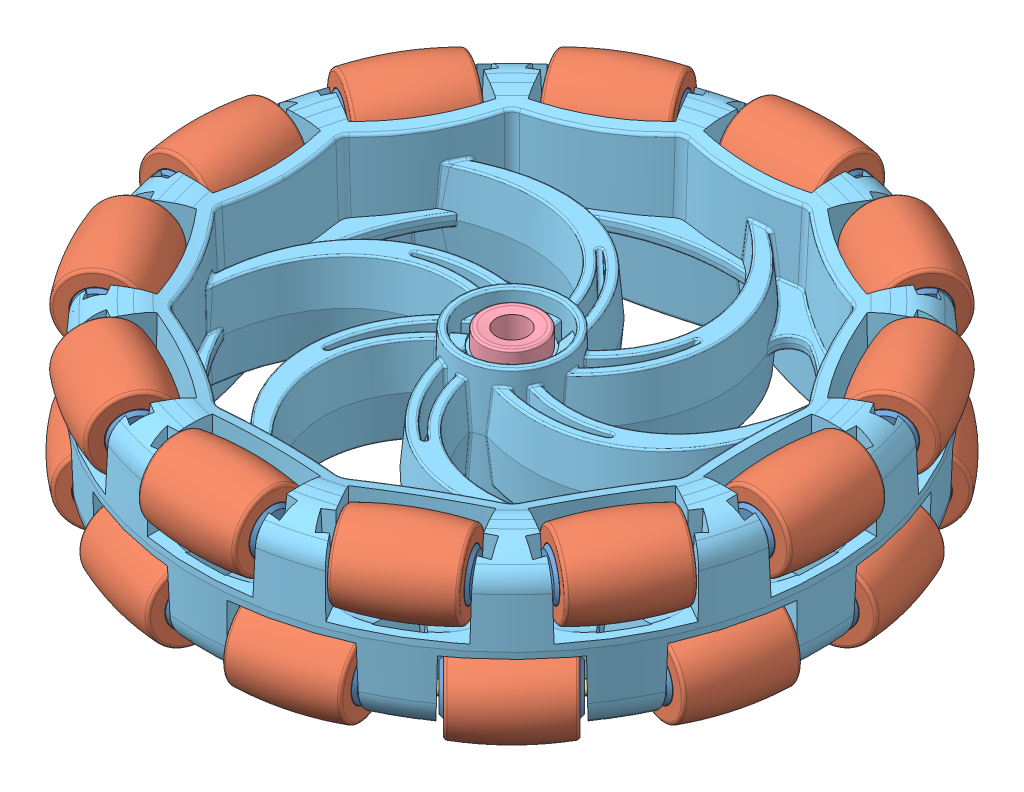
SolidWorks assembly LARGE-OMNI-WHEEL, configuration Default. Lengths in mm.
Overall size (108.3 29.85 108.3).
98 component instances, 5 part files, 0 mates.
Components (placement in the parent):
- OMNI-ROLLER-1: OMNI-ROLLER [Default] at (23.2326 8 -40.2802) x (0.866025 0 0.5) z (-0.5 0 0.866025) size (22 13.22 13.22)
  - ROLLER-INSERT-1: ROLLER-INSERT [Default] at origin size (16.6 8 8)
  - ROLLER-RUBBER-1: ROLLER-RUBBER [Default] at origin size (15.6 13.22 13.22)
  - ROLLER-SHAFT-1: ROLLER-SHAFT [Default] at origin size (22 2 2)
- OMNI-ROLLER-2: OMNI-ROLLER [Default] at (40.2671 8 23.2553) x (0.5 0 -0.866025) z (0.866025 0 0.5) size (22 13.22 13.22)
  - ROLLER-INSERT-1: ROLLER-INSERT [Default] at origin size (16.6 8 8)
  - ROLLER-RUBBER-1: ROLLER-RUBBER [Default] at origin size (15.6 13.22 13.22)
  - ROLLER-SHAFT-1: ROLLER-SHAFT [Default] at origin size (22 2 2)
- OMNI-ROLLER-3: OMNI-ROLLER [Default] at (0.013 8 46.5) size (22 13.22 13.22)
  - ROLLER-INSERT-1: ROLLER-INSERT [Default] at origin size (16.6 8 8)
  - ROLLER-RUBBER-1: ROLLER-RUBBER [Default] at origin size (15.6 13.22 13.22)
  - ROLLER-SHAFT-1: ROLLER-SHAFT [Default] at origin size (22 2 2)
- OMNI-ROLLER-4: OMNI-ROLLER [Default] at (12.0398 -8 44.9143) x (0.965926 0 -0.258819) z (0.258819 0 0.965926) size (22 13.22 13.22)
  - ROLLER-INSERT-1: ROLLER-INSERT [Default] at origin size (16.6 8 8)
  - ROLLER-RUBBER-1: ROLLER-RUBBER [Default] at origin size (15.6 13.22 13.22)
  - ROLLER-SHAFT-1: ROLLER-SHAFT [Default] at origin size (22 2 2)
- OMNI-ROLLER-5: OMNI-ROLLER [Default] at (44.9116 -8 -12.0497) x (0.258819 0 0.965926) z (-0.965926 0 0.258819) size (22 13.22 13.22)
  - ROLLER-INSERT-1: ROLLER-INSERT [Default] at origin size (16.6 8 8)
  - ROLLER-RUBBER-1: ROLLER-RUBBER [Default] at origin size (15.6 13.22 13.22)
  - ROLLER-SHAFT-1: ROLLER-SHAFT [Default] at origin size (22 2 2)
- OMNI-ROLLER-6: OMNI-ROLLER [Default] at (-12.0287 -8 -44.9173) x (0.965926 0 -0.258819) z (0.258819 0 0.965926) size (22 13.22 13.22)
  - ROLLER-INSERT-1: ROLLER-INSERT [Default] at origin size (16.6 8 8)
  - ROLLER-RUBBER-1: ROLLER-RUBBER [Default] at origin size (15.6 13.22 13.22)
  - ROLLER-SHAFT-1: ROLLER-SHAFT [Default] at origin size (22 2 2)
- OMNI-ROLLER-7: OMNI-ROLLER [Default] at (-23.2609 8 40.2639) x (0.866025 0 0.5) z (-0.5 0 0.866025) size (22 13.22 13.22)
  - ROLLER-INSERT-1: ROLLER-INSERT [Default] at origin size (16.6 8 8)
  - ROLLER-RUBBER-1: ROLLER-RUBBER [Default] at origin size (15.6 13.22 13.22)
  - ROLLER-SHAFT-1: ROLLER-SHAFT [Default] at origin size (22 2 2)
- OMNI-ROLLER-8: OMNI-ROLLER [Default] at (-12.0305 -8 44.9168) x (0.965926 0 0.258819) z (-0.258819 0 0.965926) size (22 13.22 13.22)
  - ROLLER-INSERT-1: ROLLER-INSERT [Default] at origin size (16.6 8 8)
  - ROLLER-RUBBER-1: ROLLER-RUBBER [Default] at origin size (15.6 13.22 13.22)
  - ROLLER-SHAFT-1: ROLLER-SHAFT [Default] at origin size (22 2 2)
- OMNI-ROLLER-9: OMNI-ROLLER [Default] at (12.0345 -8 -44.9157) x (0.965926 0 0.258819) z (-0.258819 0 0.965926) size (22 13.22 13.22)
  - ROLLER-INSERT-1: ROLLER-INSERT [Default] at origin size (16.6 8 8)
  - ROLLER-RUBBER-1: ROLLER-RUBBER [Default] at origin size (15.6 13.22 13.22)
  - ROLLER-SHAFT-1: ROLLER-SHAFT [Default] at origin size (22 2 2)
- OMNI-ROLLER-10: OMNI-ROLLER [Default] at (-40.2754 8 23.241) x (0.5 0 0.866025) z (-0.866025 0 0.5) size (22 13.22 13.22)
  - ROLLER-INSERT-1: ROLLER-INSERT [Default] at origin size (16.6 8 8)
  - ROLLER-RUBBER-1: ROLLER-RUBBER [Default] at origin size (15.6 13.22 13.22)
  - ROLLER-SHAFT-1: ROLLER-SHAFT [Default] at origin size (22 2 2)
- OMNI-ROLLER-11: OMNI-ROLLER [Default] at (-40.2738 8 -23.2437) x (0.5 0 -0.866025) z (0.866025 0 0.5) size (22 13.22 13.22)
  - ROLLER-INSERT-1: ROLLER-INSERT [Default] at origin size (16.6 8 8)
  - ROLLER-RUBBER-1: ROLLER-RUBBER [Default] at origin size (15.6 13.22 13.22)
  - ROLLER-SHAFT-1: ROLLER-SHAFT [Default] at origin size (22 2 2)
- OMNI-ROLLER-12: OMNI-ROLLER [Default] at (46.5 8 0) x (0 0 1) z (0 1 0) size (22 13.22 13.22)
  - ROLLER-INSERT-1: ROLLER-INSERT [Default] at origin size (16.6 8 8)
  - ROLLER-RUBBER-1: ROLLER-RUBBER [Default] at origin size (15.6 13.22 13.22)
  - ROLLER-SHAFT-1: ROLLER-SHAFT [Default] at origin size (22 2 2)
- OMNI-ROLLER-13: OMNI-ROLLER [Default] at (-0.0255 8 -46.5) size (22 13.22 13.22)
  - ROLLER-INSERT-1: ROLLER-INSERT [Default] at origin size (16.6 8 8)
  - ROLLER-RUBBER-1: ROLLER-RUBBER [Default] at origin size (15.6 13.22 13.22)
  - ROLLER-SHAFT-1: ROLLER-SHAFT [Default] at origin size (22 2 2)
- OMNI-ROLLER-14: OMNI-ROLLER [Default] at (23.2429 8 40.2743) x (0.866025 0 -0.5) z (0.5 0 0.866025) size (22 13.22 13.22)
  - ROLLER-INSERT-1: ROLLER-INSERT [Default] at origin size (16.6 8 8)
  - ROLLER-RUBBER-1: ROLLER-RUBBER [Default] at origin size (15.6 13.22 13.22)
  - ROLLER-SHAFT-1: ROLLER-SHAFT [Default] at origin size (22 2 2)
- OMNI-ROLLER-15: OMNI-ROLLER [Default] at (-44.9187 -8 12.0234) x (0.258819 0 0.965926) z (-0.965926 0 0.258819) size (22 13.22 13.22)
  - ROLLER-INSERT-1: ROLLER-INSERT [Default] at origin size (16.6 8 8)
  - ROLLER-RUBBER-1: ROLLER-RUBBER [Default] at origin size (15.6 13.22 13.22)
  - ROLLER-SHAFT-1: ROLLER-SHAFT [Default] at origin size (22 2 2)
- OMNI-ROLLER-16: OMNI-ROLLER [Default] at (-44.9129 -8 -12.0449) x (0.258819 0 -0.965926) z (0.965926 0 0.258819) size (22 13.22 13.22)
  - ROLLER-INSERT-1: ROLLER-INSERT [Default] at origin size (16.6 8 8)
  - ROLLER-RUBBER-1: ROLLER-RUBBER [Default] at origin size (15.6 13.22 13.22)
  - ROLLER-SHAFT-1: ROLLER-SHAFT [Default] at origin size (22 2 2)
- OMNI-ROLLER-17: OMNI-ROLLER [Default] at (-23.2538 8 -40.268) x (0.866025 0 -0.5) z (0.5 0 0.866025) size (22 13.22 13.22)
  - ROLLER-INSERT-1: ROLLER-INSERT [Default] at origin size (16.6 8 8)
  - ROLLER-RUBBER-1: ROLLER-RUBBER [Default] at origin size (15.6 13.22 13.22)
  - ROLLER-SHAFT-1: ROLLER-SHAFT [Default] at origin size (22 2 2)
- OMNI-ROLLER-18: OMNI-ROLLER [Default] at (32.8529 -8 -32.9081) x (0.707107 0 0.707107) z (-0.707107 0 0.707107) size (22 13.22 13.22)
  - ROLLER-INSERT-1: ROLLER-INSERT [Default] at origin size (16.6 8 8)
  - ROLLER-RUBBER-1: ROLLER-RUBBER [Default] at origin size (15.6 13.22 13.22)
  - ROLLER-SHAFT-1: ROLLER-SHAFT [Default] at origin size (22 2 2)
- OMNI-ROLLER-19: OMNI-ROLLER [Default] at (40.2648 8 -23.2593) x (0.5 0 0.866025) z (-0.866025 0 0.5) size (22 13.22 13.22)
  - ROLLER-INSERT-1: ROLLER-INSERT [Default] at origin size (16.6 8 8)
  - ROLLER-RUBBER-1: ROLLER-RUBBER [Default] at origin size (15.6 13.22 13.22)
  - ROLLER-SHAFT-1: ROLLER-SHAFT [Default] at origin size (22 2 2)
- LARGE-OMNI-HUB-INSERT-1: LARGE-OMNI-HUB-INSERT [Default] x (-1 0 0) z (0 1 0) size (9.68 9.68 19.05)
- OMNI-ROLLER-20: OMNI-ROLLER [Default] at (32.8647 -8 32.8962) x (0.707107 0 -0.707107) z (0.707107 0 0.707107) size (22 13.22 13.22)
  - ROLLER-INSERT-1: ROLLER-INSERT [Default] at origin size (16.6 8 8)
  - ROLLER-RUBBER-1: ROLLER-RUBBER [Default] at origin size (15.6 13.22 13.22)
  - ROLLER-SHAFT-1: ROLLER-SHAFT [Default] at origin size (22 2 2)
- OMNI-ROLLER-21: OMNI-ROLLER [Default] at (44.9169 -8 12.0301) x (0.258819 0 -0.965926) z (0.965926 0 0.258819) size (22 13.22 13.22)
  - ROLLER-INSERT-1: ROLLER-INSERT [Default] at origin size (16.6 8 8)
  - ROLLER-RUBBER-1: ROLLER-RUBBER [Default] at origin size (15.6 13.22 13.22)
  - ROLLER-SHAFT-1: ROLLER-SHAFT [Default] at origin size (22 2 2)
- LARGE-OMNI-HUB-1: LARGE-OMNI-HUB [Default] at origin size (102 28.49 102)
- OMNI-ROLLER-22: OMNI-ROLLER [Default] at (-46.5 8 -0.0142) x (0 0 -1) z (1 0 0) size (22 13.22 13.22)
  - ROLLER-INSERT-1: ROLLER-INSERT [Default] at origin size (16.6 8 8)
  - ROLLER-RUBBER-1: ROLLER-RUBBER [Default] at origin size (15.6 13.22 13.22)
  - ROLLER-SHAFT-1: ROLLER-SHAFT [Default] at origin size (22 2 2)
- OMNI-ROLLER-23: OMNI-ROLLER [Default] at (-32.8835 -8 32.8775) x (0.707107 0 0.707107) z (-0.707107 0 0.707107) size (22 13.22 13.22)
  - ROLLER-INSERT-1: ROLLER-INSERT [Default] at origin size (16.6 8 8)
  - ROLLER-RUBBER-1: ROLLER-RUBBER [Default] at origin size (15.6 13.22 13.22)
  - ROLLER-SHAFT-1: ROLLER-SHAFT [Default] at origin size (22 2 2)
- OMNI-ROLLER-24: OMNI-ROLLER [Default] at (-32.8436 -8 -32.9173) x (0.707107 0 -0.707107) z (0.707107 0 0.707107) size (22 13.22 13.22)
  - ROLLER-INSERT-1: ROLLER-INSERT [Default] at origin size (16.6 8 8)
  - ROLLER-RUBBER-1: ROLLER-RUBBER [Default] at origin size (15.6 13.22 13.22)
  - ROLLER-SHAFT-1: ROLLER-SHAFT [Default] at origin size (22 2 2)
